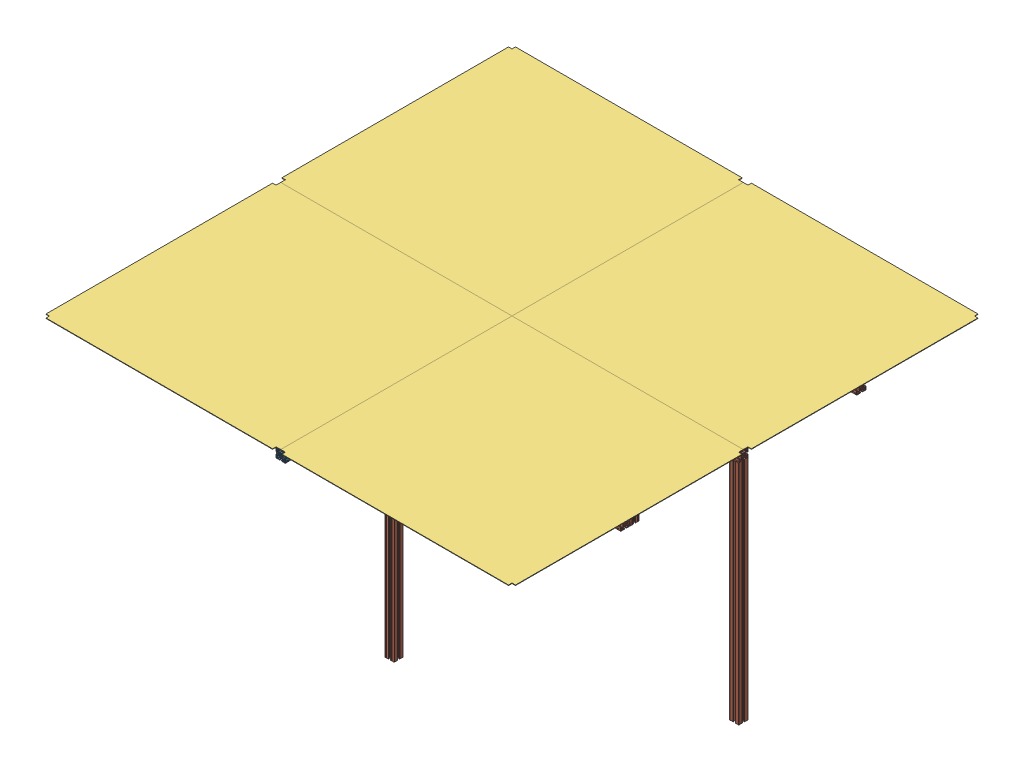
SolidWorks assembly Fundo_Mod_Clean, configuration Valor predeterminado. Lengths in mm.
Overall size (2030 1022.12 2030).
15 component instances, 3 part files, 13 mates.
Components (placement in the parent):
- Perfil_Alum_4x4x200-1: Perfil_Alum_4x4x200 [Valor predeterminado] at (75.7311 2000 25.6945) size (40 40 2000)
- Perfil_Alum_4x4x98-1: Perfil_Alum_4x4x98 [Valor predeterminado] at (-434.2689 2000 25.6945) x (0 0 -1) z (1 0 0) size (40 40 980)
- Perfil_Alum_4x4x98-2: Perfil_Alum_4x4x98 [Valor predeterminado] at (586.3147 2000 25.6943) x (0 0 -1) z (1 0 0) size (40 40 980)
- Perfil_Alum_4x4x98-3: Perfil_Alum_4x4x98 [Valor predeterminado] at (-434.2689 2000 -484.3055) x (0 0 -1) z (1 0 0) size (40 40 980)
- Perfil_Alum_4x4x98-4: Perfil_Alum_4x4x98 [Valor predeterminado] at (585.7311 2000 -484.3055) x (0 0 -1) z (1 0 0) size (40 40 980)
- Perfil_Alum_4x4x98-5: Perfil_Alum_4x4x98 [Valor predeterminado] at (-434.2689 2000 535.6945) x (0 0 -1) z (1 0 0) size (40 40 980)
- Perfil_Alum_4x4x98-6: Perfil_Alum_4x4x98 [Valor predeterminado] at (585.7311 2000 535.6945) x (0 0 -1) z (1 0 0) size (40 40 980)
- Chapa_Fundo_Mod_Clean-1: Chapa_Fundo_Mod_Clean [Valor predeterminado] at (583.2024 2021.1231 -481.8055) size (1015 2 1015)
- Chapa_Fundo_Mod_Clean-2: Chapa_Fundo_Mod_Clean [Valor predeterminado] at (-431.7976 2021.1231 -481.8055) x (0 0 -1) z (1 0 0) size (1015 2 1015)
- Chapa_Fundo_Mod_Clean-3: Chapa_Fundo_Mod_Clean [Valor predeterminado] at (-431.7976 2021.1231 533.1945) x (-1 0 0) z (0 0 -1) size (1015 2 1015)
- Chapa_Fundo_Mod_Clean-4: Chapa_Fundo_Mod_Clean [Valor predeterminado] at (583.2024 2021.1231 533.1945) x (0 0 1) z (-1 0 0) size (1015 2 1015)
- Perfil_Alum_4x4x98-7: Perfil_Alum_4x4x98 [Valor predeterminado] at (75.7311 1490 -484.3055) x (1 0 0) z (0 -1 0) size (40 40 980)
- Perfil_Alum_4x4x98-8: Perfil_Alum_4x4x98 [Valor predeterminado] at (1056.3147 1490 25.6943) x (1 0 0) z (0 -1 0) size (40 40 980)
- Perfil_Alum_4x4x98-9: Perfil_Alum_4x4x98 [Valor predeterminado] at (-904.2689 1490 25.6945) x (1 0 0) z (0 -1 0) size (40 40 980)
- Perfil_Alum_4x4x98-10: Perfil_Alum_4x4x98 [Valor predeterminado] at (75.7311 1490 535.6945) x (1 0 0) z (0 -1 0) size (40 40 980)
Mates (geometry in assembly coordinates):
- Distância1: distance = 980 mm: line of Perfil_Alum_4x4x200-1 through (95.7311 1981.5 -974.3055) axis (0 1 0); line of Perfil_Alum_4x4x98-2 through (96.3147 1981.5 5.6943) axis (0 1 0)
- Distância2: distance = 980 mm: line of Perfil_Alum_4x4x200-1 through (55.7311 1985.6 -974.3055) axis (0 -1 0); line of Perfil_Alum_4x4x98-1 through (55.7311 1981.5 5.6945) axis (0 1 0)
- Distância3: distance = 470 mm: line of Perfil_Alum_4x4x98-4 through (95.7311 2014.4 -504.3055) axis (0 1 0); line of Perfil_Alum_4x4x200-1 through (95.7311 2014.4 -974.3055) axis (0 1 0)
- Distância4: distance = 470 mm: line of Perfil_Alum_4x4x200-1 through (55.7311 2018.5 -974.3055) axis (0 -1 0); line of Perfil_Alum_4x4x98-3 through (55.7311 2014.4 -504.3055) axis (0 1 0)
- Distância5: distance = 470 mm: line of Perfil_Alum_4x4x98-6 through (95.7311 2018.5 555.6945) axis (0 -1 0); line of Perfil_Alum_4x4x200-1 through (95.7311 2014.4 1025.6945) axis (0 1 0)
- Distância6: distance = 470 mm: line of Perfil_Alum_4x4x98-5 through (55.7311 2018.5 555.6945) axis (0 -1 0); line of Perfil_Alum_4x4x200-1 through (55.7311 2018.5 1025.6945) axis (0 -1 0)
- Coincidente16: coincident: point of Chapa_Fundo_Mod_Clean-1; unknown of Chapa_Fundo_Mod_Clean-2
- Coincidente20: coincident: unknown of Chapa_Fundo_Mod_Clean-1; unknown of Chapa_Fundo_Mod_Clean-3
- Coincidente21: coincident: unknown of Chapa_Fundo_Mod_Clean-1; unknown of Chapa_Fundo_Mod_Clean-4
- Coincidente24: coincident: unknown of Perfil_Alum_4x4x98-1; unknown of Perfil_Alum_4x4x98-9
- Coincidente25: coincident: unknown of Perfil_Alum_4x4x98-2; unknown of Perfil_Alum_4x4x98-8
- Distância7: distance = 470 mm: line of Perfil_Alum_4x4x200-1 through (57.2311 1980 1025.6945) axis (1 0 0); line of Perfil_Alum_4x4x98-10 through (61.3311 1980 555.6945) axis (-1 0 0)
- Distância8: distance = 470 mm: line of Perfil_Alum_4x4x98-7 through (57.2311 1980 -504.3055) axis (1 0 0); line of Perfil_Alum_4x4x200-1 through (57.2311 1980 -974.3055) axis (1 0 0)
